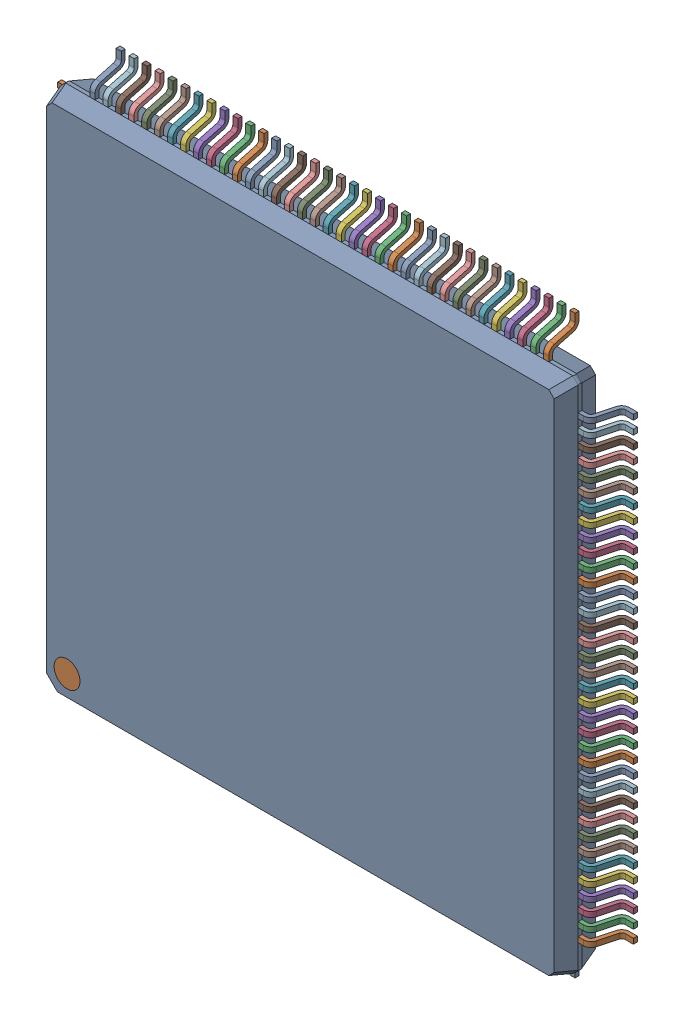
SolidWorks assembly LQFP-144, configuration 默认. Lengths in mm.
Overall size (22.2 22.2 1.89).
147 component instances, 3 part files, 0 mates.
Components (placement in the parent):
- User Library-LQFP144-3-1: User Library-LQFP144-3 [默认] x (0 1 0) z (1 0 0) size (22.2 1.89 22.2)
  - case-1: case [默认] at (0 1 0) size (19.96 1.6 19.96)
  - pin-28-1: pin-28 [默认] at (-8.75 0.9224 9.9806) size (0.2 1.16 1.12)
  - pin-28-2: pin-28 [默认] at (-8.25 0.9224 9.9806) size (0.2 1.16 1.12)
  - pin-28-3: pin-28 [默认] at (-7.75 0.9224 9.9806) size (0.2 1.16 1.12)
  - pin-28-4: pin-28 [默认] at (-7.25 0.9224 9.9806) size (0.2 1.16 1.12)
  - pin-28-5: pin-28 [默认] at (-6.75 0.9224 9.9806) size (0.2 1.16 1.12)
  - pin-28-6: pin-28 [默认] at (-6.25 0.9224 9.9806) size (0.2 1.16 1.12)
  - pin-28-7: pin-28 [默认] at (-5.75 0.9224 9.9806) size (0.2 1.16 1.12)
  - pin-28-8: pin-28 [默认] at (-5.25 0.9224 9.9806) size (0.2 1.16 1.12)
  - pin-28-9: pin-28 [默认] at (-4.75 0.9224 9.9806) size (0.2 1.16 1.12)
  - pin-28-10: pin-28 [默认] at (-4.25 0.9224 9.9806) size (0.2 1.16 1.12)
  - pin-28-11: pin-28 [默认] at (-3.75 0.9224 9.9806) size (0.2 1.16 1.12)
  - pin-28-12: pin-28 [默认] at (-3.25 0.9224 9.9806) size (0.2 1.16 1.12)
  - pin-28-13: pin-28 [默认] at (-2.75 0.9224 9.9806) size (0.2 1.16 1.12)
  - pin-28-14: pin-28 [默认] at (-2.25 0.9224 9.9806) size (0.2 1.16 1.12)
  - pin-28-15: pin-28 [默认] at (-1.75 0.9224 9.9806) size (0.2 1.16 1.12)
  - pin-28-16: pin-28 [默认] at (-1.25 0.9224 9.9806) size (0.2 1.16 1.12)
  - pin-28-17: pin-28 [默认] at (-0.75 0.9224 9.9806) size (0.2 1.16 1.12)
  - pin-28-18: pin-28 [默认] at (-0.25 0.9224 9.9806) size (0.2 1.16 1.12)
  - pin-28-19: pin-28 [默认] at (0.25 0.9224 9.9806) size (0.2 1.16 1.12)
  - pin-28-20: pin-28 [默认] at (0.75 0.9224 9.9806) size (0.2 1.16 1.12)
  - pin-28-21: pin-28 [默认] at (1.25 0.9224 9.9806) size (0.2 1.16 1.12)
  - pin-28-22: pin-28 [默认] at (1.75 0.9224 9.9806) size (0.2 1.16 1.12)
  - pin-28-23: pin-28 [默认] at (2.25 0.9224 9.9806) size (0.2 1.16 1.12)
  - pin-28-24: pin-28 [默认] at (2.75 0.9224 9.9806) size (0.2 1.16 1.12)
  - pin-28-25: pin-28 [默认] at (3.25 0.9224 9.9806) size (0.2 1.16 1.12)
  - pin-28-26: pin-28 [默认] at (3.75 0.9224 9.9806) size (0.2 1.16 1.12)
  - pin-28-27: pin-28 [默认] at (4.25 0.9224 9.9806) size (0.2 1.16 1.12)
  - pin-28-28: pin-28 [默认] at (4.75 0.9224 9.9806) size (0.2 1.16 1.12)
  - pin-28-29: pin-28 [默认] at (5.25 0.9224 9.9806) size (0.2 1.16 1.12)
  - pin-28-30: pin-28 [默认] at (5.75 0.9224 9.9806) size (0.2 1.16 1.12)
  - pin-28-31: pin-28 [默认] at (6.25 0.9224 9.9806) size (0.2 1.16 1.12)
  - pin-28-32: pin-28 [默认] at (6.75 0.9224 9.9806) size (0.2 1.16 1.12)
  - pin-28-33: pin-28 [默认] at (7.25 0.9224 9.9806) size (0.2 1.16 1.12)
  - pin-28-34: pin-28 [默认] at (7.75 0.9224 9.9806) size (0.2 1.16 1.12)
  - pin-28-35: pin-28 [默认] at (8.25 0.9224 9.9806) size (0.2 1.16 1.12)
  - pin-28-36: pin-28 [默认] at (8.75 0.9224 9.9806) size (0.2 1.16 1.12)
  - pin-28-37: pin-28 [默认] at (9.9806 0.9224 8.75) x (0 0 -1) z (1 0 0) size (0.2 1.16 1.12)
  - pin-28-38: pin-28 [默认] at (9.9806 0.9224 8.25) x (0 0 -1) z (1 0 0) size (0.2 1.16 1.12)
  - pin-28-39: pin-28 [默认] at (9.9806 0.9224 7.75) x (0 0 -1) z (1 0 0) size (0.2 1.16 1.12)
  - pin-28-40: pin-28 [默认] at (9.9806 0.9224 7.25) x (0 0 -1) z (1 0 0) size (0.2 1.16 1.12)
  - pin-28-41: pin-28 [默认] at (9.9806 0.9224 6.75) x (0 0 -1) z (1 0 0) size (0.2 1.16 1.12)
  - pin-28-42: pin-28 [默认] at (9.9806 0.9224 6.25) x (0 0 -1) z (1 0 0) size (0.2 1.16 1.12)
  - pin-28-43: pin-28 [默认] at (9.9806 0.9224 5.75) x (0 0 -1) z (1 0 0) size (0.2 1.16 1.12)
  - pin-28-44: pin-28 [默认] at (9.9806 0.9224 5.25) x (0 0 -1) z (1 0 0) size (0.2 1.16 1.12)
  - pin-28-45: pin-28 [默认] at (9.9806 0.9224 4.75) x (0 0 -1) z (1 0 0) size (0.2 1.16 1.12)
  - pin-28-46: pin-28 [默认] at (9.9806 0.9224 4.25) x (0 0 -1) z (1 0 0) size (0.2 1.16 1.12)
  - pin-28-47: pin-28 [默认] at (9.9806 0.9224 3.75) x (0 0 -1) z (1 0 0) size (0.2 1.16 1.12)
  - pin-28-48: pin-28 [默认] at (9.9806 0.9224 3.25) x (0 0 -1) z (1 0 0) size (0.2 1.16 1.12)
  - pin-28-49: pin-28 [默认] at (9.9806 0.9224 2.75) x (0 0 -1) z (1 0 0) size (0.2 1.16 1.12)
  - pin-28-50: pin-28 [默认] at (9.9806 0.9224 2.25) x (0 0 -1) z (1 0 0) size (0.2 1.16 1.12)
  - pin-28-51: pin-28 [默认] at (9.9806 0.9224 1.75) x (0 0 -1) z (1 0 0) size (0.2 1.16 1.12)
  - pin-28-52: pin-28 [默认] at (9.9806 0.9224 1.25) x (0 0 -1) z (1 0 0) size (0.2 1.16 1.12)
  - pin-28-53: pin-28 [默认] at (9.9806 0.9224 0.75) x (0 0 -1) z (1 0 0) size (0.2 1.16 1.12)
  - pin-28-54: pin-28 [默认] at (9.9806 0.9224 0.25) x (0 0 -1) z (1 0 0) size (0.2 1.16 1.12)
  - pin-28-55: pin-28 [默认] at (9.9806 0.9224 -0.25) x (0 0 -1) z (1 0 0) size (0.2 1.16 1.12)
  - pin-28-56: pin-28 [默认] at (9.9806 0.9224 -0.75) x (0 0 -1) z (1 0 0) size (0.2 1.16 1.12)
  - pin-28-57: pin-28 [默认] at (9.9806 0.9224 -1.25) x (0 0 -1) z (1 0 0) size (0.2 1.16 1.12)
  - pin-28-58: pin-28 [默认] at (9.9806 0.9224 -1.75) x (0 0 -1) z (1 0 0) size (0.2 1.16 1.12)
  - pin-28-59: pin-28 [默认] at (9.9806 0.9224 -2.25) x (0 0 -1) z (1 0 0) size (0.2 1.16 1.12)
  - pin-28-60: pin-28 [默认] at (9.9806 0.9224 -2.75) x (0 0 -1) z (1 0 0) size (0.2 1.16 1.12)
  - pin-28-61: pin-28 [默认] at (9.9806 0.9224 -3.25) x (0 0 -1) z (1 0 0) size (0.2 1.16 1.12)
  - pin-28-62: pin-28 [默认] at (9.9806 0.9224 -3.75) x (0 0 -1) z (1 0 0) size (0.2 1.16 1.12)
  - pin-28-63: pin-28 [默认] at (9.9806 0.9224 -4.25) x (0 0 -1) z (1 0 0) size (0.2 1.16 1.12)
  - pin-28-64: pin-28 [默认] at (9.9806 0.9224 -4.75) x (0 0 -1) z (1 0 0) size (0.2 1.16 1.12)
  - pin-28-65: pin-28 [默认] at (9.9806 0.9224 -5.25) x (0 0 -1) z (1 0 0) size (0.2 1.16 1.12)
  - pin-28-66: pin-28 [默认] at (9.9806 0.9224 -5.75) x (0 0 -1) z (1 0 0) size (0.2 1.16 1.12)
  - pin-28-67: pin-28 [默认] at (9.9806 0.9224 -6.25) x (0 0 -1) z (1 0 0) size (0.2 1.16 1.12)
  - pin-28-68: pin-28 [默认] at (9.9806 0.9224 -6.75) x (0 0 -1) z (1 0 0) size (0.2 1.16 1.12)
  - pin-28-69: pin-28 [默认] at (9.9806 0.9224 -7.25) x (0 0 -1) z (1 0 0) size (0.2 1.16 1.12)
  - pin-28-70: pin-28 [默认] at (9.9806 0.9224 -7.75) x (0 0 -1) z (1 0 0) size (0.2 1.16 1.12)
  - pin-28-71: pin-28 [默认] at (9.9806 0.9224 -8.25) x (0 0 -1) z (1 0 0) size (0.2 1.16 1.12)
  - pin-28-72: pin-28 [默认] at (9.9806 0.9224 -8.75) x (0 0 -1) z (1 0 0) size (0.2 1.16 1.12)
  - pin-28-73: pin-28 [默认] at (8.75 0.9224 -9.9806) x (-1 0 0) z (0 0 -1) size (0.2 1.16 1.12)
  - pin-28-74: pin-28 [默认] at (8.25 0.9224 -9.9806) x (-1 0 0) z (0 0 -1) size (0.2 1.16 1.12)
  - pin-28-75: pin-28 [默认] at (7.75 0.9224 -9.9806) x (-1 0 0) z (0 0 -1) size (0.2 1.16 1.12)
  - pin-28-76: pin-28 [默认] at (7.25 0.9224 -9.9806) x (-1 0 0) z (0 0 -1) size (0.2 1.16 1.12)
  - pin-28-77: pin-28 [默认] at (6.75 0.9224 -9.9806) x (-1 0 0) z (0 0 -1) size (0.2 1.16 1.12)
  - pin-28-78: pin-28 [默认] at (6.25 0.9224 -9.9806) x (-1 0 0) z (0 0 -1) size (0.2 1.16 1.12)
  - pin-28-79: pin-28 [默认] at (5.75 0.9224 -9.9806) x (-1 0 0) z (0 0 -1) size (0.2 1.16 1.12)
  - pin-28-80: pin-28 [默认] at (5.25 0.9224 -9.9806) x (-1 0 0) z (0 0 -1) size (0.2 1.16 1.12)
  - pin-28-81: pin-28 [默认] at (4.75 0.9224 -9.9806) x (-1 0 0) z (0 0 -1) size (0.2 1.16 1.12)
  - pin-28-82: pin-28 [默认] at (4.25 0.9224 -9.9806) x (-1 0 0) z (0 0 -1) size (0.2 1.16 1.12)
  - pin-28-83: pin-28 [默认] at (3.75 0.9224 -9.9806) x (-1 0 0) z (0 0 -1) size (0.2 1.16 1.12)
  - pin-28-84: pin-28 [默认] at (3.25 0.9224 -9.9806) x (-1 0 0) z (0 0 -1) size (0.2 1.16 1.12)
  - pin-28-85: pin-28 [默认] at (2.75 0.9224 -9.9806) x (-1 0 0) z (0 0 -1) size (0.2 1.16 1.12)
  - pin-28-86: pin-28 [默认] at (2.25 0.9224 -9.9806) x (-1 0 0) z (0 0 -1) size (0.2 1.16 1.12)
  - pin-28-87: pin-28 [默认] at (1.75 0.9224 -9.9806) x (-1 0 0) z (0 0 -1) size (0.2 1.16 1.12)
  - pin-28-88: pin-28 [默认] at (1.25 0.9224 -9.9806) x (-1 0 0) z (0 0 -1) size (0.2 1.16 1.12)
  - pin-28-89: pin-28 [默认] at (0.75 0.9224 -9.9806) x (-1 0 0) z (0 0 -1) size (0.2 1.16 1.12)
  - pin-28-90: pin-28 [默认] at (0.25 0.9224 -9.9806) x (-1 0 0) z (0 0 -1) size (0.2 1.16 1.12)
  - pin-28-91: pin-28 [默认] at (-0.25 0.9224 -9.9806) x (-1 0 0) z (0 0 -1) size (0.2 1.16 1.12)
  - pin-28-92: pin-28 [默认] at (-0.75 0.9224 -9.9806) x (-1 0 0) z (0 0 -1) size (0.2 1.16 1.12)
  - pin-28-93: pin-28 [默认] at (-1.25 0.9224 -9.9806) x (-1 0 0) z (0 0 -1) size (0.2 1.16 1.12)
  - pin-28-94: pin-28 [默认] at (-1.75 0.9224 -9.9806) x (-1 0 0) z (0 0 -1) size (0.2 1.16 1.12)
  - pin-28-95: pin-28 [默认] at (-2.25 0.9224 -9.9806) x (-1 0 0) z (0 0 -1) size (0.2 1.16 1.12)
  - pin-28-96: pin-28 [默认] at (-2.75 0.9224 -9.9806) x (-1 0 0) z (0 0 -1) size (0.2 1.16 1.12)
  - pin-28-97: pin-28 [默认] at (-3.25 0.9224 -9.9806) x (-1 0 0) z (0 0 -1) size (0.2 1.16 1.12)
  - pin-28-98: pin-28 [默认] at (-3.75 0.9224 -9.9806) x (-1 0 0) z (0 0 -1) size (0.2 1.16 1.12)
  - pin-28-99: pin-28 [默认] at (-4.25 0.9224 -9.9806) x (-1 0 0) z (0 0 -1) size (0.2 1.16 1.12)
  - pin-28-100: pin-28 [默认] at (-4.75 0.9224 -9.9806) x (-1 0 0) z (0 0 -1) size (0.2 1.16 1.12)
  - pin-28-101: pin-28 [默认] at (-5.25 0.9224 -9.9806) x (-1 0 0) z (0 0 -1) size (0.2 1.16 1.12)
  - pin-28-102: pin-28 [默认] at (-5.75 0.9224 -9.9806) x (-1 0 0) z (0 0 -1) size (0.2 1.16 1.12)
  - pin-28-103: pin-28 [默认] at (-6.25 0.9224 -9.9806) x (-1 0 0) z (0 0 -1) size (0.2 1.16 1.12)
  - pin-28-104: pin-28 [默认] at (-6.75 0.9224 -9.9806) x (-1 0 0) z (0 0 -1) size (0.2 1.16 1.12)
  - pin-28-105: pin-28 [默认] at (-7.25 0.9224 -9.9806) x (-1 0 0) z (0 0 -1) size (0.2 1.16 1.12)
  - pin-28-106: pin-28 [默认] at (-7.75 0.9224 -9.9806) x (-1 0 0) z (0 0 -1) size (0.2 1.16 1.12)
  - pin-28-107: pin-28 [默认] at (-8.25 0.9224 -9.9806) x (-1 0 0) z (0 0 -1) size (0.2 1.16 1.12)
  - pin-28-108: pin-28 [默认] at (-8.75 0.9224 -9.9806) x (-1 0 0) z (0 0 -1) size (0.2 1.16 1.12)
  - pin-28-109: pin-28 [默认] at (-9.9806 0.9224 -8.75) x (0 0 1) z (-1 0 0) size (0.2 1.16 1.12)
  - pin-28-110: pin-28 [默认] at (-9.9806 0.9224 -8.25) x (0 0 1) z (-1 0 0) size (0.2 1.16 1.12)
  - pin-28-111: pin-28 [默认] at (-9.9806 0.9224 -7.75) x (0 0 1) z (-1 0 0) size (0.2 1.16 1.12)
  - pin-28-112: pin-28 [默认] at (-9.9806 0.9224 -7.25) x (0 0 1) z (-1 0 0) size (0.2 1.16 1.12)
  - pin-28-113: pin-28 [默认] at (-9.9806 0.9224 -6.75) x (0 0 1) z (-1 0 0) size (0.2 1.16 1.12)
  - pin-28-114: pin-28 [默认] at (-9.9806 0.9224 -6.25) x (0 0 1) z (-1 0 0) size (0.2 1.16 1.12)
  - pin-28-115: pin-28 [默认] at (-9.9806 0.9224 -5.75) x (0 0 1) z (-1 0 0) size (0.2 1.16 1.12)
  - pin-28-116: pin-28 [默认] at (-9.9806 0.9224 -5.25) x (0 0 1) z (-1 0 0) size (0.2 1.16 1.12)
  - pin-28-117: pin-28 [默认] at (-9.9806 0.9224 -4.75) x (0 0 1) z (-1 0 0) size (0.2 1.16 1.12)
  - pin-28-118: pin-28 [默认] at (-9.9806 0.9224 -4.25) x (0 0 1) z (-1 0 0) size (0.2 1.16 1.12)
  - pin-28-119: pin-28 [默认] at (-9.9806 0.9224 -3.75) x (0 0 1) z (-1 0 0) size (0.2 1.16 1.12)
  - pin-28-120: pin-28 [默认] at (-9.9806 0.9224 -3.25) x (0 0 1) z (-1 0 0) size (0.2 1.16 1.12)
  - pin-28-121: pin-28 [默认] at (-9.9806 0.9224 -2.75) x (0 0 1) z (-1 0 0) size (0.2 1.16 1.12)
  - pin-28-122: pin-28 [默认] at (-9.9806 0.9224 -2.25) x (0 0 1) z (-1 0 0) size (0.2 1.16 1.12)
  - pin-28-123: pin-28 [默认] at (-9.9806 0.9224 -1.75) x (0 0 1) z (-1 0 0) size (0.2 1.16 1.12)
  - pin-28-124: pin-28 [默认] at (-9.9806 0.9224 -1.25) x (0 0 1) z (-1 0 0) size (0.2 1.16 1.12)
  - pin-28-125: pin-28 [默认] at (-9.9806 0.9224 -0.75) x (0 0 1) z (-1 0 0) size (0.2 1.16 1.12)
  - pin-28-126: pin-28 [默认] at (-9.9806 0.9224 -0.25) x (0 0 1) z (-1 0 0) size (0.2 1.16 1.12)
  - pin-28-127: pin-28 [默认] at (-9.9806 0.9224 0.25) x (0 0 1) z (-1 0 0) size (0.2 1.16 1.12)
  - pin-28-128: pin-28 [默认] at (-9.9806 0.9224 0.75) x (0 0 1) z (-1 0 0) size (0.2 1.16 1.12)
  - pin-28-129: pin-28 [默认] at (-9.9806 0.9224 1.25) x (0 0 1) z (-1 0 0) size (0.2 1.16 1.12)
  - pin-28-130: pin-28 [默认] at (-9.9806 0.9224 1.75) x (0 0 1) z (-1 0 0) size (0.2 1.16 1.12)
  - pin-28-131: pin-28 [默认] at (-9.9806 0.9224 2.25) x (0 0 1) z (-1 0 0) size (0.2 1.16 1.12)
  - pin-28-132: pin-28 [默认] at (-9.9806 0.9224 2.75) x (0 0 1) z (-1 0 0) size (0.2 1.16 1.12)
  - pin-28-133: pin-28 [默认] at (-9.9806 0.9224 3.25) x (0 0 1) z (-1 0 0) size (0.2 1.16 1.12)
  - pin-28-134: pin-28 [默认] at (-9.9806 0.9224 3.75) x (0 0 1) z (-1 0 0) size (0.2 1.16 1.12)
  - pin-28-135: pin-28 [默认] at (-9.9806 0.9224 4.25) x (0 0 1) z (-1 0 0) size (0.2 1.16 1.12)
  - pin-28-136: pin-28 [默认] at (-9.9806 0.9224 4.75) x (0 0 1) z (-1 0 0) size (0.2 1.16 1.12)
  - pin-28-137: pin-28 [默认] at (-9.9806 0.9224 5.25) x (0 0 1) z (-1 0 0) size (0.2 1.16 1.12)
  - pin-28-138: pin-28 [默认] at (-9.9806 0.9224 5.75) x (0 0 1) z (-1 0 0) size (0.2 1.16 1.12)
  - pin-28-139: pin-28 [默认] at (-9.9806 0.9224 6.25) x (0 0 1) z (-1 0 0) size (0.2 1.16 1.12)
  - pin-28-140: pin-28 [默认] at (-9.9806 0.9224 6.75) x (0 0 1) z (-1 0 0) size (0.2 1.16 1.12)
  - pin-28-141: pin-28 [默认] at (-9.9806 0.9224 7.25) x (0 0 1) z (-1 0 0) size (0.2 1.16 1.12)
  - pin-28-142: pin-28 [默认] at (-9.9806 0.9224 7.75) x (0 0 1) z (-1 0 0) size (0.2 1.16 1.12)
  - pin-28-143: pin-28 [默认] at (-9.9806 0.9224 8.25) x (0 0 1) z (-1 0 0) size (0.2 1.16 1.12)
  - pin-28-144: pin-28 [默认] at (-9.9806 0.9224 8.75) x (0 0 1) z (-1 0 0) size (0.2 1.16 1.12)
  - circle-1: circle [默认] at (-9 1.7 -9) size (1 0.1 1)
